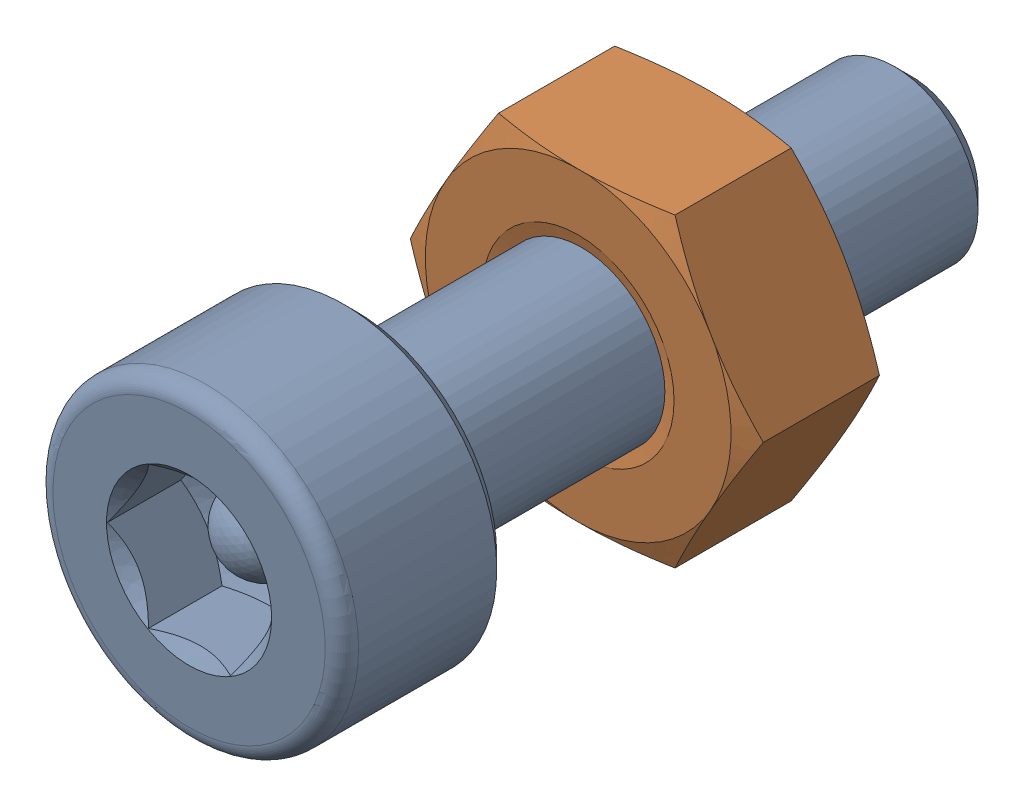
SolidWorks assembly Screw and Nut M3x010_017-1, configuration Varsayılan. Lengths in mm.
Overall size (6.35 5.5 13.14).
2 component instances, 2 part files, 0 mates.
Components (placement in the parent):
- M3x10-Screw016-1-1: M3x10-Screw016-1 [Varsayılan] at origin size (5.5 5.5 13.14)
- M3-Nut048-1-1: M3-Nut048-1 [Varsayılan] at (0 0 -4) x (-1 0 0) z (0 0 -1) size (6.35 5.5 2.4)
